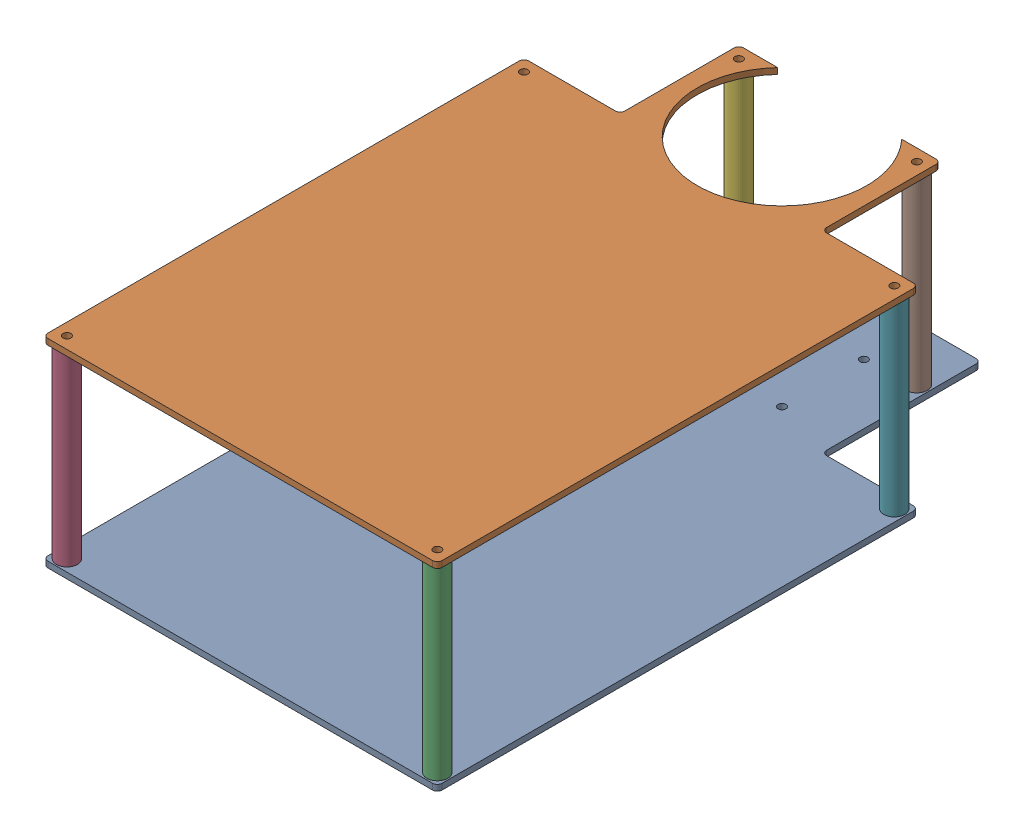
SolidWorks assembly Robot Mount, configuration Default. Lengths in mm.
Overall size (210.85 106.35 342.16).
8 component instances, 3 part files, 17 mates.
Components (placement in the parent):
- Robot Base V2-1: Robot Base V2 [Default] at (564.7906 858.5271 1414.1475) size (210.82 3.17 342.16)
- Checkerboard V2-1: Checkerboard V2 [Default] at (564.7906 961.7021 1414.1475) size (210.85 3.17 320.68)
- Spacers-1: Spacers [Default] at (756.5606 861.7021 1420.4975) size (11.18 100 11.18)
- Spacers-2: Spacers [Default] at (558.4406 861.7021 1420.4975) size (11.18 100 11.18)
- Spacers-3: Spacers [Default] at (558.4406 861.7021 1176.0225) size (11.18 100 11.18)
- Spacers-4: Spacers [Default] at (609.8756 861.7021 1112.5225) size (11.18 100 11.18)
- Spacers-5: Spacers [Default] at (756.5606 861.7021 1176.0225) size (11.18 100 11.18)
- Spacers-6: Spacers [Default] at (705.1256 861.7021 1112.5225) size (11.18 100 11.18)
Mates (geometry in assembly coordinates):
- Concentric2: concentric aligned: cylinder of Robot Base V2-1 through (756.5606 858.5271 1420.4975) axis (0 1 0) radius 2.0955; cylinder of Checkerboard V2-1 through (756.5606 961.7021 1420.4975) axis (0 1 0) radius 2.0955
- Concentric3: concentric aligned: cylinder of Robot Base V2-1 through (558.4406 858.5271 1420.4975) axis (0 1 0) radius 2.0955; cylinder of Checkerboard V2-1 through (558.4406 961.7021 1420.4975) axis (0 1 0) radius 2.0955
- Concentric5: concentric anti-aligned: cylinder of Robot Base V2-1 through (756.5606 858.5271 1420.4975) axis (0 1 0) radius 2.0955; cylinder of Spacers-1 through (756.5606 961.7021 1420.4975) axis (0 -1 0) radius 5.588
- Coincident4: coincident anti-aligned: plane of Checkerboard V2-1 through (564.7906 961.7021 1414.1475) normal (0 -1 0); plane of Spacers-1 through (756.5606 961.7021 1420.4975) normal (0 1 0)
- Parallel2: parallel anti-aligned: plane of Robot Base V2-1 through (564.7906 861.7021 1414.1475) normal (0 1 0); plane of Spacers-1 through (756.5606 861.7021 1420.4975) normal (0 -1 0)
- Coincident8: coincident anti-aligned: plane of Robot Base V2-1 through (564.7906 861.7021 1414.1475) normal (0 1 0); plane of Spacers-1 through (756.5606 861.7021 1420.4975) normal (0 -1 0)
- Concentric6: concentric anti-aligned: cylinder of Robot Base V2-1 through (558.4406 858.5271 1420.4975) axis (0 1 0) radius 2.0955; cylinder of Spacers-2 through (558.4406 961.7021 1420.4975) axis (0 -1 0) radius 5.588
- Coincident9: coincident anti-aligned: plane of Checkerboard V2-1 through (564.7906 961.7021 1414.1475) normal (0 -1 0); plane of Spacers-2 through (558.4406 961.7021 1420.4975) normal (0 1 0)
- Coincident10: coincident anti-aligned: plane of Robot Base V2-1 through (564.7906 861.7021 1414.1475) normal (0 1 0); plane of Spacers-2 through (558.4406 861.7021 1420.4975) normal (0 -1 0)
- Concentric8: concentric anti-aligned: cylinder of Robot Base V2-1 through (756.5606 858.5271 1176.0225) axis (0 1 0) radius 2.0955; cylinder of Spacers-5 through (756.5606 961.7021 1176.0225) axis (0 -1 0) radius 5.588
- Concentric9: concentric anti-aligned: cylinder of Robot Base V2-1 through (705.1256 858.5271 1112.5225) axis (0 1 0) radius 2.0955; cylinder of Spacers-6 through (705.1256 961.7021 1112.5225) axis (0 -1 0) radius 5.588
- Concentric10: concentric anti-aligned: cylinder of Checkerboard V2-1 through (558.4406 961.7021 1176.0225) axis (0 1 0) radius 2.0955; cylinder of Spacers-3 through (558.4406 961.7021 1176.0225) axis (0 -1 0) radius 5.588
- Concentric11: concentric anti-aligned: circle of Checkerboard V2-1; cylinder of Spacers-4 through (609.8756 961.7021 1112.5225) axis (0 -1 0) radius 5.588
- Coincident11: coincident anti-aligned: plane of Checkerboard V2-1 through (564.7906 961.7021 1414.1475) normal (0 -1 0); plane of Spacers-5 through (756.5606 961.7021 1176.0225) normal (0 1 0)
- Coincident12: coincident anti-aligned: plane of Checkerboard V2-1 through (564.7906 961.7021 1414.1475) normal (0 -1 0); plane of Spacers-6 through (705.1256 961.7021 1112.5225) normal (0 1 0)
- Coincident13: coincident anti-aligned: plane of Checkerboard V2-1 through (564.7906 961.7021 1414.1475) normal (0 -1 0); plane of Spacers-3 through (558.4406 961.7021 1176.0225) normal (0 1 0)
- Coincident14: coincident anti-aligned: plane of Checkerboard V2-1 through (564.7906 961.7021 1414.1475) normal (0 -1 0); circle of Spacers-4
